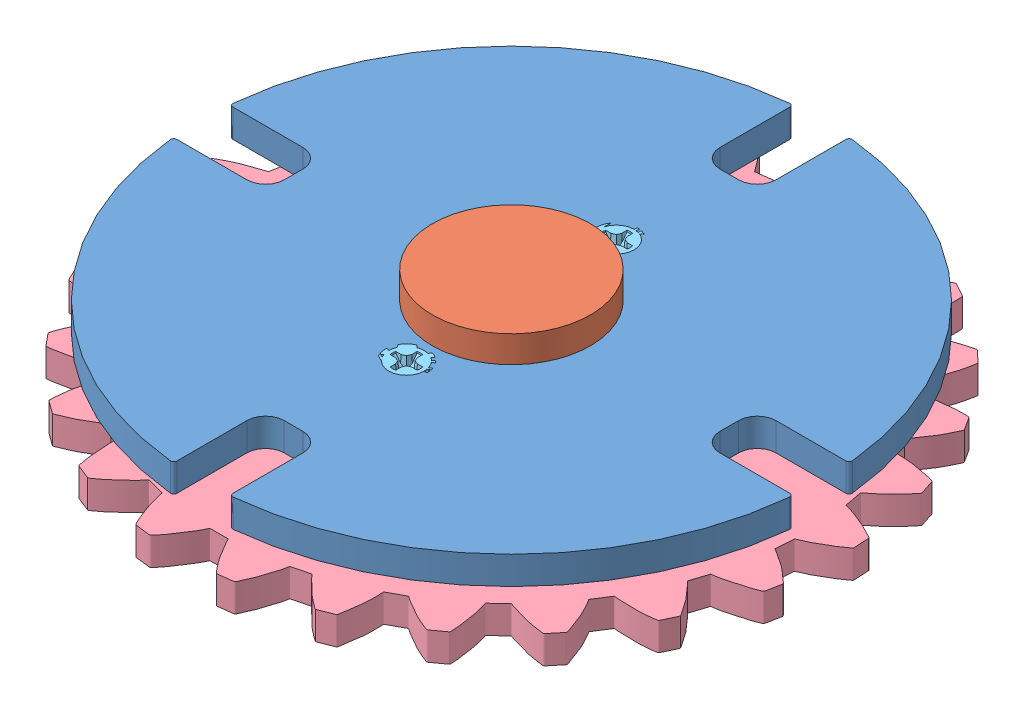
SolidWorks assembly Assem3, configuration Default. Lengths in mm.
Overall size (188.23 25.6 124.49).
6 component instances, 5 part files, 12 mates.
Components (placement in the parent):
- transfer_plate-4: transfer_plate [Default] at (0 -4.5661 0) size (188.23 4.5 124.49)
- handoff_shaft-1: handoff_shaft [Default] at (0 -4.5661 0) x (-0.685538 0 0.728037) z (-0.728037 0 -0.685538) size (25.4 25.6 25.4)
- transfer_spacer-1: transfer_spacer [Default] at (0 -9.0661 0) x (0 0 -1) z (0 1 0) size (40 40 4.5)
- 25 tooth large gear2-2: 25 tooth large gear2 [Default] at (0 -13.5661 0) size (105.94 4.5 105.74)
- 91771A169-1: 91771A169 [91771A169] at (0 -2.1743 16.8627) x (1 0 0) z (0 1 0) size (6.65 6.65 15.37)
- 91771A169-2: 91771A169 [91771A169] at (0 -2.1743 -16.8627) x (1 0 0) z (0 1 0) size (6.65 6.65 15.37)
Mates (geometry in assembly coordinates):
- Coincident37: coincident anti-aligned: plane of transfer_plate-4 through (0 -4.5661 0) normal (0 -1 0); plane of transfer_spacer-1 through (0 -4.5661 0) normal (0 1 0)
- Coincident46: coincident aligned: plane of transfer_plate-4 through (0 -4.5661 0) normal (1 0 0); plane of 25 tooth large gear2-2 through (0 -13.5661 0) normal (1 0 0)
- Coincident49: coincident anti-aligned: plane of transfer_spacer-1 through (0 -9.0661 0) normal (0 -1 0); plane of 25 tooth large gear2-2 through (3.7854 -9.0661 -48.4816) normal (0 1 0)
- Coincident51: coincident aligned: plane of transfer_plate-4 through (0 -4.5661 0) normal (0 1 0); plane of handoff_shaft-1
- Concentric1: concentric aligned: cylinder of transfer_plate-4 through (0 -0.0661 0) axis (0 -1 0) radius 12.7; cylinder of handoff_shaft-1 through (0 40.155 0) axis (0 -1 0) radius 12.7
- Concentric3: concentric aligned: cylinder of transfer_spacer-1 through (0 -4.5661 0) axis (0 -1 0) radius 12.7; cylinder of 25 tooth large gear2-2 through (0 -9.0661 0) axis (0 -1 0) radius 12.7
- Concentric4: concentric aligned: cylinder of handoff_shaft-1 through (0 40.155 0) axis (0 -1 0) radius 12.7; cylinder of transfer_spacer-1 through (0 -4.5661 0) axis (0 -1 0) radius 12.7
- Parallel1: parallel anti-aligned: plane of transfer_plate-4 through (0 -4.5661 0) normal (1 0 0); plane of transfer_spacer-1
- Coincident55: coincident aligned: plane of transfer_plate-4 through (0 -0.0661 0) normal (0 1 0); plane of 91771A169-1 through (0 -0.0661 15.1101) normal (0 1 0)
- Concentric7: concentric anti-aligned: cylinder of transfer_plate-4 through (0 -0.0661 16.8627) axis (0 1 0) radius 1.7272; circle of 91771A169-1
- Coincident56: coincident aligned: plane of transfer_plate-4 through (0 -0.0661 0) normal (0 1 0); plane of 91771A169-2 through (0 -0.0661 -18.6153) normal (0 1 0)
- Concentric8: concentric anti-aligned: cylinder of transfer_plate-4 through (0 -0.0661 -16.8627) axis (0 1 0) radius 1.7272; circle of 91771A169-2
